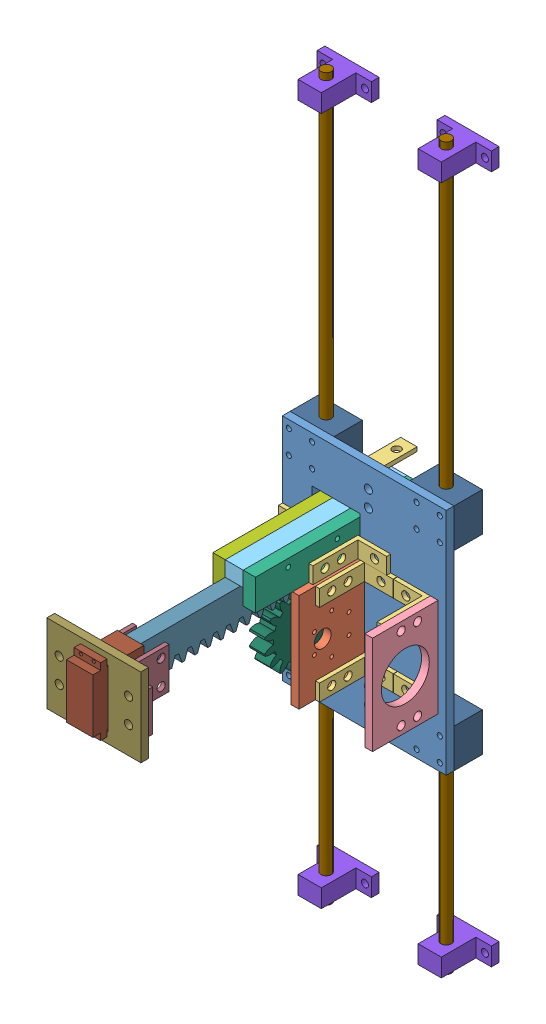
SolidWorks assembly part placer asm, configuration Default. Lengths in mm.
Overall size (135 558.8 245.72).
31 component instances, 15 part files, 54 mates.
Components (placement in the parent):
- mounting plate-1: mounting plate [Default] at (27.1569 24.9758 169.7319) size (127 177.8 5.99)
- front motor plate-1: front motor plate [Default] at (90.8368 139.2758 175.7263) x (0 -1 0) z (-1 0 0) size (76.2 50.8 5.99)
- gearmotor mounting brackets-1: gearmotor mounting brackets [Default] at (141.8424 75.7758 175.7263) x (0 0 1) z (0 -1 0) size (38.1 25.4 12.7)
- rear motor plate-1: rear motor plate [Default] at (147.8368 139.2758 175.7263) x (0 -1 0) z (-1 0 0) size (76.2 50.8 5.99)
- rack back plate-1: rack back plate [Default] at (62.2477 151.5948 255.1013) x (1 0 0) z (0 1 0) size (13.97 127 11.81)
- rack right plate-1: rack right plate [Default] at (85.7427 163.4058 255.1013) x (-1 0 0) z (0 -1 0) size (9.53 127 24.13)
- rack left plate-1: rack left plate [Default] at (62.2477 163.4058 255.1013) x (-1 0 0) z (0 -1 0) size (9.53 127 38.1)
- gearmotor mounting brackets-2: gearmotor mounting brackets [Default] at (141.8424 139.2758 175.7263) x (0 0 1) z (0 -1 0) size (38.1 25.4 12.7)
- gearmotor mounting brackets-3: gearmotor mounting brackets [Default] at (90.8368 126.5758 175.7263) x (0 0 1) z (0 1 0) size (38.1 25.4 12.7)
- gearmotor mounting brackets-4: gearmotor mounting brackets [Default] at (90.8368 63.0758 175.7263) x (0 0 1) z (0 1 0) size (38.1 25.4 12.7)
- gearmotor mounting brackets-5: gearmotor mounting brackets [Default] at (85.7427 139.2758 175.7263) x (0 0 1) z (0 1 0) size (38.1 25.4 12.7)
- gearmotor mounting brackets-6: gearmotor mounting brackets [Default] at (52.7227 144.3558 175.7263) x (0 0 1) z (0 -1 0) size (38.1 25.4 12.7)
- rails_asm-1: rails_asm [Default] at (129.0895 -70.2762 138.5497) x (1 0 0) z (0 -1 0) size (135 32.8 558.8)
  - Linear Rail Shaft Guide-1: Linear Rail Shaft Guide [Default] at (-12.9326 0.1821 32.8794) size (42 32.8 14)
  - Linear Rail Shaft Guide-2: Linear Rail Shaft Guide [Default] at (-12.9326 0.1821 -500.7446) size (42 32.8 14)
  - Linear Rail Shaft Guide-3: Linear Rail Shaft Guide [Default] at (-105.9326 0.1821 32.8794) size (42 32.8 14)
  - Linear Rail Shaft Guide-4: Linear Rail Shaft Guide [Default] at (-105.9326 0.1821 -500.7446) size (42 32.8 14)
  - 8mm rod-1: 8mm rod [Default] at (8.0674 20.1821 -506.1132) x (0.336006 0.94186 0) z (0 0 1) size (8 8 558.8)
  - 8mm rod-2: 8mm rod [Default] at (-84.9326 20.1821 -506.1132) x (0.967966 -0.251082 0) z (0 0 1) size (8 8 558.8)
  - linear bearing platform-1: linear bearing platform [Default] at (-8.9326 9.1821 -125.252) size (34 22 30)
  - linear bearing platform-2: linear bearing platform [Default] at (-8.9326 9.1821 -273.052) size (34 22 30)
  - linear bearing platform-3: linear bearing platform [Default] at (-101.9326 9.1821 -125.252) size (34 22 30)
  - linear bearing platform-4: linear bearing platform [Default] at (-101.9326 9.1821 -273.052) size (34 22 30)
- gearmotor mounting brackets-8: gearmotor mounting brackets [Default] at (87.4819 202.7758 169.7319) x (0 -1 0) z (1 0 0) size (38.1 25.4 12.7)
- gearmotor mounting brackets-9: gearmotor mounting brackets [Default] at (100.1819 24.9758 169.7319) x (0 1 0) z (-1 0 0) size (38.1 25.4 12.7)
- servo-1: servo [Default] at (57.8567 153.533 334.3104) x (0 -0.999999 -0.00124) z (0 -0.00124 0.999999) size (52.33 20.5 39.5)
- servo mount-1: servo mount [Default] at (57.1067 155.0052 356.7659) x (0 -0.999999 -0.00124) z (0 -0.00124 0.999999) size (61 72.8 5.99)
- servo mounting brackets-1: servo mounting brackets [Default] at (57.1067 116.6302 356.7183) x (0 0.00124 -0.999999) z (0 0.999999 0.00124) size (38.1 25.4 31.75)
- servo mounting brackets-2: servo mounting brackets [Default] at (79.1067 148.3802 356.7576) x (0 0.00124 -0.999999) z (0 -0.999999 -0.00124) size (38.1 25.4 31.75)
- rack spur rectangular_ai-2: rack spur rectangular_ai [Inch - Rack-spur - rectangular 8DP 20PA 0.465FW 1PH 8L---SAll] at (62.2477 151.5948 334.2962) x (0 0 -1) z (-1 0 0) size (203.2 28.57 11.81)
- spur gear_ai-2: spur gear_ai [Inch - Spur gear 8DP 16T 20PA 0.465FW ---S16N3.0H2.0L0.03125N] at (62.2477 101.1758 208.1263) size (11.81 56.32 56.32)
Mates (geometry in assembly coordinates):
- Coincident1: coincident anti-aligned: plane of mounting plate-1 through (27.1569 24.9758 175.7263) normal (0 0 1); plane of front motor plate-1 through (84.8424 139.2758 175.7263) normal (0 0 -1)
- Distance1: distance = 38.1 mm aligned: plane of front motor plate-1 through (84.8424 63.0758 175.7263) normal (0 -1 0); plane of mounting plate-1 through (27.1569 24.9758 175.7263) normal (0 -1 0)
- Coincident4: coincident anti-aligned: plane of mounting plate-1 through (27.1569 24.9758 175.7263) normal (0 0 1); plane of rear motor plate-1 through (141.8424 139.2758 175.7263) normal (0 0 -1)
- Coincident7: coincident aligned: plane of front motor plate-1 through (84.8424 139.2758 175.7263) normal (0 1 0); plane of rear motor plate-1 through (141.8424 139.2758 175.7263) normal (0 1 0)
- Distance2: distance = 51.0056 mm anti-aligned: plane of front motor plate-1 through (90.8368 139.2758 175.7263) normal (1 0 0); plane of rear motor plate-1 through (141.8424 139.2758 175.7263) normal (-1 0 0)
- Coincident11: coincident anti-aligned: plane of rack back plate-1 through (62.2477 163.4058 255.1013) normal (-1 0 0); plane of rack left plate-1 through (62.2477 125.3058 255.1013) normal (1 0 0)
- Coincident12: coincident aligned: plane of rack back plate-1 through (62.2477 163.4058 255.1013) normal (0 0 1); plane of rack left plate-1 through (62.2477 125.3058 255.1013) normal (0 0 1)
- Coincident13: coincident aligned: plane of rack back plate-1 through (62.2477 163.4058 255.1013) normal (0 1 0); plane of rack left plate-1 through (62.2477 163.4058 255.1013) normal (0 1 0)
- Coincident14: coincident aligned: plane of rack back plate-1 through (62.2477 163.4058 255.1013) normal (0 1 0); plane of rack right plate-1 through (85.7427 163.4058 255.1013) normal (0 1 0)
- Coincident15: coincident aligned: plane of rack back plate-1 through (62.2477 163.4058 255.1013) normal (0 0 1); plane of rack right plate-1 through (85.7427 139.2758 255.1013) normal (0 0 1)
- Coincident16: coincident anti-aligned: plane of rack back plate-1 through (76.2177 163.4058 255.1013) normal (1 0 0); plane of rack right plate-1 through (76.2177 139.2758 255.1013) normal (-1 0 0)
- Concentric2: concentric anti-aligned: cylinder of gearmotor mounting brackets-1 through (141.8424 69.4258 204.3013) axis (-1 0 0) radius 3.175; cylinder of rear motor plate-1 through (141.8424 69.4258 204.3013) axis (1 0 0) radius 3.175
- Coincident19: coincident anti-aligned: plane of mounting plate-1 through (27.1569 24.9758 175.7263) normal (0 0 1); plane of gearmotor mounting brackets-1 through (141.8424 63.0758 175.7263) normal (0 0 -1)
- Coincident20: coincident anti-aligned: plane of gearmotor mounting brackets-1 through (141.8424 63.0758 213.8263) normal (1 0 0); plane of rear motor plate-1 through (141.8424 139.2758 175.7263) normal (-1 0 0)
- Distance8: distance = 100.33 mm aligned: plane of rack left plate-1 through (62.2477 125.3058 255.1013) normal (0 -1 0); plane of mounting plate-1 through (27.1569 24.9758 175.7263) normal (0 -1 0)
- Concentric3: concentric anti-aligned: cylinder of rear motor plate-1 through (141.8424 132.9258 191.6013) axis (1 0 0) radius 3.175; cylinder of gearmotor mounting brackets-2 through (141.8424 132.9258 191.6013) axis (-1 0 0) radius 3.175
- Coincident30: coincident anti-aligned: plane of rear motor plate-1 through (141.8424 139.2758 175.7263) normal (-1 0 0); plane of gearmotor mounting brackets-2 through (141.8424 126.5758 213.8263) normal (1 0 0)
- Concentric4: concentric anti-aligned: cylinder of rear motor plate-1 through (141.8424 132.9258 204.3013) axis (1 0 0) radius 3.175; cylinder of gearmotor mounting brackets-2 through (141.8424 132.9258 204.3013) axis (-1 0 0) radius 3.175
- Coincident31: coincident anti-aligned: plane of front motor plate-1 through (90.8368 139.2758 175.7263) normal (1 0 0); plane of gearmotor mounting brackets-3 through (90.8368 139.2758 213.8263) normal (-1 0 0)
- Concentric5: concentric aligned: cylinder of front motor plate-1 through (84.8424 132.9258 191.6013) axis (1 0 0) radius 3.175; cylinder of gearmotor mounting brackets-3 through (90.8368 132.9258 191.6013) axis (1 0 0) radius 3.175
- Coincident32: coincident aligned: cylinder of front motor plate-1 through (84.8424 132.9258 204.3013) axis (1 0 0) radius 3.175; circle of gearmotor mounting brackets-3
- Coincident33: coincident anti-aligned: plane of front motor plate-1 through (90.8368 139.2758 175.7263) normal (1 0 0); plane of gearmotor mounting brackets-4 through (90.8368 75.7758 213.8263) normal (-1 0 0)
- Concentric6: concentric aligned: cylinder of front motor plate-1 through (84.8424 69.4258 191.6013) axis (1 0 0) radius 3.175; cylinder of gearmotor mounting brackets-4 through (90.8368 69.4258 191.6013) axis (1 0 0) radius 3.175
- Concentric7: concentric aligned: cylinder of front motor plate-1 through (84.8424 69.4258 204.3013) axis (1 0 0) radius 3.175; cylinder of gearmotor mounting brackets-4 through (90.8368 69.4258 204.3013) axis (1 0 0) radius 3.175
- Coincident36: coincident anti-aligned: plane of mounting plate-1 through (27.1569 24.9758 175.7263) normal (0 0 1); plane of gearmotor mounting brackets-5 through (85.7427 151.9758 175.7263) normal (0 0 -1)
- Coincident37: coincident anti-aligned: plane of rack right plate-1 through (85.7427 139.2758 255.1013) normal (1 0 0); plane of gearmotor mounting brackets-5 through (85.7427 151.9758 213.8263) normal (-1 0 0)
- Concentric10: concentric anti-aligned: cylinder of rack right plate-1 through (114.3177 145.6258 191.6013) axis (-1 0 0) radius 3.175; cylinder of gearmotor mounting brackets-5 through (85.7427 145.6258 191.6013) axis (1 0 0) radius 3.175
- Coincident38: coincident anti-aligned: plane of mounting plate-1 through (27.1569 24.9758 175.7263) normal (0 0 1); plane of gearmotor mounting brackets-6 through (52.7227 131.6558 175.7263) normal (0 0 -1)
- Coincident39: coincident anti-aligned: plane of rack left plate-1 through (52.7227 125.3058 255.1013) normal (-1 0 0); plane of gearmotor mounting brackets-6 through (52.7227 131.6558 213.8263) normal (1 0 0)
- Coincident40: coincident anti-aligned: plane of mounting plate-1 through (27.1569 24.9758 169.7319) normal (0 0 -1); plane of rails_asm-1/linear bearing platform-1 through (120.1569 24.9758 169.7319) normal (0 0 1)
- Concentric15: concentric anti-aligned: cylinder of mounting plate-1 through (32.1569 196.7758 175.7263) axis (0 0 -1) radius 2; cylinder of rails_asm-1/linear bearing platform-4 through (32.1569 196.7758 147.7319) axis (0 0 1) radius 2
- Concentric16: concentric anti-aligned: cylinder of mounting plate-1 through (32.1569 48.9758 175.7263) axis (0 0 -1) radius 2; cylinder of rails_asm-1/linear bearing platform-3 through (32.1569 48.9758 147.7319) axis (0 0 1) radius 2
- Coincident41: coincident anti-aligned: plane of mounting plate-1 through (27.1569 24.9758 169.7319) normal (0 0 -1); plane of gearmotor mounting brackets-8 through (100.1819 164.6758 169.7319) normal (0 0 1)
- Concentric17: concentric aligned: cylinder of mounting plate-1 through (93.8319 174.2008 175.7263) axis (0 0 -1) radius 3.175; cylinder of gearmotor mounting brackets-8 through (93.8319 174.2008 169.7319) axis (0 0 -1) radius 3.175
- Concentric18: concentric aligned: cylinder of mounting plate-1 through (93.8319 186.9008 175.7263) axis (0 0 -1) radius 3.175; cylinder of gearmotor mounting brackets-8 through (93.8319 186.9008 169.7319) axis (0 0 -1) radius 3.175
- Coincident42: coincident anti-aligned: plane of mounting plate-1 through (27.1569 24.9758 169.7319) normal (0 0 -1); plane of gearmotor mounting brackets-9 through (87.4819 63.0758 169.7319) normal (0 0 1)
- Concentric19: concentric aligned: cylinder of mounting plate-1 through (93.8319 40.8508 175.7263) axis (0 0 -1) radius 3.175; cylinder of gearmotor mounting brackets-9 through (93.8319 40.8508 169.7319) axis (0 0 -1) radius 3.175
- Concentric20: concentric aligned: cylinder of mounting plate-1 through (93.8319 53.5508 175.7263) axis (0 0 -1) radius 3.175; cylinder of gearmotor mounting brackets-9 through (93.8319 53.5508 169.7319) axis (0 0 -1) radius 3.175
- Distance9: distance = 0.1658 mm aligned: plane of mounting plate-1 through (27.1569 24.9758 175.7263) normal (-1 0 0); plane of gearmotor mounting brackets-6 through (27.3227 131.6558 175.7263) normal (-1 0 0)
- Concentric23: concentric aligned: cylinder of rack left plate-1 through (90.8227 138.0058 204.3013) axis (-1 0 0) radius 3.175; cylinder of gearmotor mounting brackets-6 through (52.7227 138.0058 204.3013) axis (-1 0 0) radius 3.175
- Coincident47: coincident anti-aligned: plane of servo-1 through (57.8567 153.4977 362.7584) normal (0 0.00124 -0.999999); plane of servo mount-1 through (57.1067 154.9977 362.7603) normal (0 -0.00124 0.999999)
- Concentric24: concentric aligned: cylinder of servo-1 through (63.1067 156.9914 367.8427) axis (0 0.00124 -0.999999) radius 1.27; cylinder of servo mount-1 through (63.1067 156.9977 362.7627) axis (0 0.00124 -0.999999) radius 1.27
- Concentric27: concentric aligned: cylinder of servo-1 through (73.1067 107.9915 367.782) axis (0 0.00124 -0.999999) radius 1.27; cylinder of servo mount-1 through (73.1067 107.9978 362.702) axis (0 0.00124 -0.999999) radius 1.27
- Concentric33: concentric aligned: cylinder of servo mount-1 through (41.2317 142.0227 362.7442) axis (0 0.00124 -0.999999) radius 3.175; cylinder of servo mounting brackets-1 through (41.2317 142.0302 356.7498) axis (0 0.00124 -0.999999) radius 3.175
- Concentric34: concentric aligned: cylinder of servo mount-1 through (41.2317 122.9728 362.7205) axis (0 0.00124 -0.999999) radius 3.175; cylinder of servo mounting brackets-1 through (41.2317 122.9802 356.7262) axis (0 0.00124 -0.999999) radius 3.175
- Coincident54: coincident anti-aligned: plane of servo mount-1 through (57.1067 155.0052 356.7659) normal (0 0.00124 -0.999999); plane of servo mounting brackets-1 through (57.1067 148.3802 356.7576) normal (0 -0.00124 0.999999)
- Coincident55: coincident anti-aligned: plane of servo mount-1 through (57.1067 155.0052 356.7659) normal (0 0.00124 -0.999999); plane of servo mounting brackets-2 through (79.1067 116.6302 356.7183) normal (0 -0.00124 0.999999)
- Concentric35: concentric aligned: cylinder of servo mount-1 through (94.9817 122.9728 362.7205) axis (0 0.00124 -0.999999) radius 3.175; cylinder of servo mounting brackets-2 through (94.9817 122.9802 356.7262) axis (0 0.00124 -0.999999) radius 3.175
- Concentric36: concentric aligned: cylinder of servo mount-1 through (94.9817 142.0227 362.7442) axis (0 0.00124 -0.999999) radius 3.175; cylinder of servo mounting brackets-2 through (94.9817 142.0302 356.7498) axis (0 0.00124 -0.999999) radius 3.175
- Distance14: distance = 6.3201 mm aligned: plane of mounting plate-1 through (154.1569 24.9758 175.7263) normal (1 0 0); plane of rear motor plate-1 through (147.8368 139.2758 175.7263) normal (1 0 0)
- Coincident57: coincident anti-aligned: plane of rack back plate-1 through (62.2477 151.5948 255.1013) normal (0 -1 0); plane of rack spur rectangular_ai-2 through (74.0587 151.5948 334.2962) normal (0 1 0)
- Coincident59: coincident anti-aligned: plane of rack left plate-1 through (62.2477 125.3058 255.1013) normal (1 0 0); plane of rack spur rectangular_ai-2 through (62.2477 123.0198 334.2962) normal (-1 0 0)
- Distance15: distance = 5.141 mm anti-aligned: plane of servo mounting brackets-1 through (57.1067 148.4274 318.6577) normal (1 0 0); plane of rack spur rectangular_ai-2 through (62.2477 123.0198 334.2962) normal (-1 0 0)
- Coincident61: coincident aligned: plane of rack spur rectangular_ai-2 through (62.2477 123.0198 334.2962) normal (-1 0 0); plane of spur gear_ai-2 through (62.2477 101.1758 208.1263) normal (-1 0 0)
